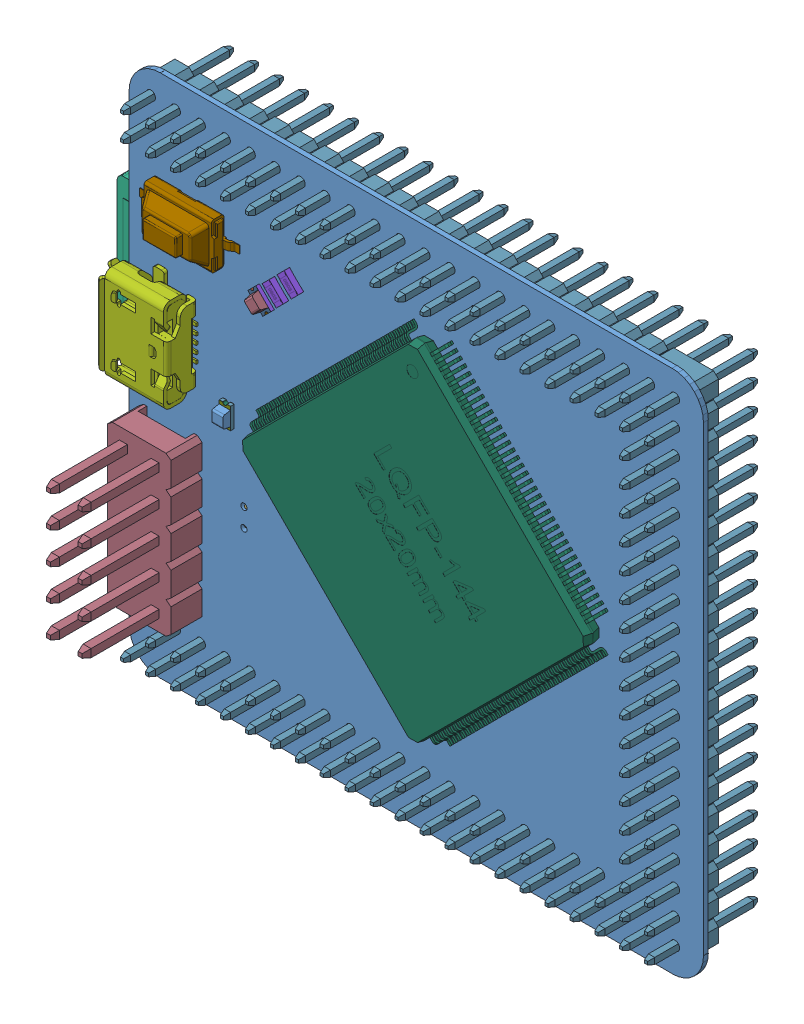
SolidWorks assembly K60最小系统, configuration Default. Lengths in mm.
Overall size (48.17 42.02 15.09).
110 component instances, 33 part files, 0 mates.
Components (placement in the parent):
- BoardK60-1: BoardK60 [默认] at (0 0 -0.3912) size (46.03 42.02 0.39)
- Y2K60-1: Y2K60 [默认] at origin size (3.3 2.6 1.1)
  - XTAL-OSC-3225-1: XTAL-OSC-3225 [默认] at (-24.3585 3.8353 -0.3912) x (1 0 0) z (0 0 -1) size (3.3 2.6 1.1)
    - User_Library-ASTX-H11_Pad-1: User_Library-ASTX-H11_Pad [默认] at origin size (3.3 2.6 0.8)
    - User_Library-ASTX-H11_Pad001-1: User_Library-ASTX-H11_Pad001 [默认] at origin size (2.8 2.4 0.24)
    - User_Library-ASTX-H11_Pad002-1: User_Library-ASTX-H11_Pad002 [默认] at origin size (2.7 2.3 0.04)
    - User_Library-ASTX-H11_ComponentPads-1: User_Library-ASTX-H11_ComponentPads [默认] at origin size (3.3 2.59 0.4)
- C1K60-1: C1K60 [默认] at origin size (1.6 0.8 0.6)
  - CAP-0603-1: CAP-0603 [默认] at (-30.5178 4.9482 -0.3912) x (-1 0 0) z (0 0 -1) size (1.6 0.8 0.6)
- C2K60-1: C2K60 [默认] at origin size (0.8 1.6 0.6)
  - CAP-0603-1: CAP-0603 [默认] at (-27.6812 3.9243 -0.3912) x (0 -1 0) z (0 0 -1) size (1.6 0.8 0.6)
- C3K60-1: C3K60 [默认] at origin size (1.6 0.8 0.6)
  - CAP-0603-1: CAP-0603 [默认] at (-29.7817 13.3652 -0.3912) x (1 0 0) z (0 0 -1) size (1.6 0.8 0.6)
- C4K60-1: C4K60 [默认] at origin size (1.6 0.8 0.6)
  - CAP-0603-1: CAP-0603 [默认] at (-29.5277 7.4724 -0.3912) x (1 0 0) z (0 0 -1) size (1.6 0.8 0.6)
- C8K60-1: C8K60 [默认] at origin size (1.6 0.8 0.6)
  - CAP-0603-1: CAP-0603 [默认] at (-25.7937 7.4724 -0.3912) x (1 0 0) z (0 0 -1) size (1.6 0.8 0.6)
- C9K60-1: C9K60 [默认] at origin size (0.8 1.6 0.6)
  - CAP-0603-1: CAP-0603 [默认] at (-11.1129 17.1069 -0.3912) x (0 -1 0) z (0 0 -1) size (1.6 0.8 0.6)
- C10K60-1: C10K60 [默认] at origin size (0.8 1.6 0.6)
  - CAP-0603-1: CAP-0603 [默认] at (-13.2127 17.1069 -0.3912) x (0 -1 0) z (0 0 -1) size (1.6 0.8 0.6)
- C11K60-1: C11K60 [默认] at origin size (0.8 1.6 0.6)
  - CAP-0603-1: CAP-0603 [默认] at (-6.9136 11.7221 -0.3912) x (0 1 0) z (0 0 -1) size (1.6 0.8 0.6)
- C12K60-1: C12K60 [默认] at origin size (0.8 1.6 0.6)
  - CAP-0603-1: CAP-0603 [默认] at (-9.0134 11.7221 -0.3912) x (0 1 0) z (0 0 -1) size (1.6 0.8 0.6)
- C13K60-1: C13K60 [默认] at origin size (0.8 1.6 0.6)
  - CAP-0603-1: CAP-0603 [默认] at (-11.1131 11.7221 -0.3912) x (0 1 0) z (0 0 -1) size (1.6 0.8 0.6)
- C14K60-1: C14K60 [默认] at origin size (0.8 1.6 0.6)
  - CAP-0603-1: CAP-0603 [默认] at (-13.2128 11.7221 -0.3912) x (0 1 0) z (0 0 -1) size (1.6 0.8 0.6)
- C15K60-1: C15K60 [默认] at origin size (0.8 1.6 0.6)
  - CAP-0603-1: CAP-0603 [默认] at (-17.0895 17.1069 -0.3912) x (0 -1 0) z (0 0 -1) size (1.6 0.8 0.6)
- C16K60-1: C16K60 [默认] at origin size (0.8 1.6 0.6)
  - CAP-0603-1: CAP-0603 [默认] at (-19.4135 17.1069 -0.3912) x (0 -1 0) z (0 0 -1) size (1.6 0.8 0.6)
- C17K60-1: C17K60 [默认] at origin size (3.2 1.6 1.6)
  - CaseA_3216-18-1: CaseA_3216-18 [默认] at (-6.5939 17.6783 -0.3912) x (1 0 0) z (0 1 0) size (3.2 1.6 1.6)
- C5K60-1: C5K60 [默认] at origin size (0.8 1.6 0.6)
  - CAP-0603-1: CAP-0603 [默认] at (-11.1637 26.6827 -0.3912) x (0 -1 0) z (0 0 -1) size (1.6 0.8 0.6)
- C6K60-1: C6K60 [默认] at origin size (0.8 1.6 0.6)
  - CAP-0603-1: CAP-0603 [默认] at (-13.2635 26.6827 -0.3912) x (0 -1 0) z (0 0 -1) size (1.6 0.8 0.6)
- C7K60-1: C7K60 [默认] at origin size (0.8 1.6 0.6)
  - CAP-0603-1: CAP-0603 [默认] at (-21.636 26.6827 -0.3912) x (0 -1 0) z (0 0 -1) size (1.6 0.8 0.6)
- D1K60-1: D1K60 [默认] at origin size (1.84 1.84 0.9)
  - LED-RED-0603-1: LED-RED-0603 [默认] at (-30.9986 26.3759 0) x (-0.707107 -0.707107 0) z (0 0 1) size (0.9 1.7 0.9)
    - User_Library-LTST-C190EKT_Pad-1: User_Library-LTST-C190EKT_Pad [默认] at origin size (0.9 1.7 0.28)
    - User_Library-LTST-C190EKT_Pad005-1: User_Library-LTST-C190EKT_Pad005 [默认] at origin size (0.35 0.15 0.31)
    - User_Library-LTST-C190EKT_Pad001-1: User_Library-LTST-C190EKT_Pad001 [默认] at origin size (0.9 1.7 0.01)
    - User_Library-LTST-C190EKT_Pad004-1: User_Library-LTST-C190EKT_Pad004 [默认] at origin size (0.35 0.15 0.31)
    - User_Library-LTST-C190EKT_Pad003-1: User_Library-LTST-C190EKT_Pad003 [默认] at origin size (0.8 1.7 0.02)
    - User_Library-LTST-C190EKT_Lens-1: User_Library-LTST-C190EKT_Lens [默认] at origin size (0.9 1.15 0.6)
- D2K60-1: D2K60 [默认] at origin size (0.9 1.7 0.9)
  - LED-BLUE-0603-1: LED-BLUE-0603 [默认] at (-33.7639 17.0687 0) size (0.9 1.7 0.9)
    - User_Library-LTST-C190TBKT_Pad-1: User_Library-LTST-C190TBKT_Pad [默认] at origin size (0.9 1.7 0.28)
    - User_Library-LTST-C190TBKT_Pad005-1: User_Library-LTST-C190TBKT_Pad005 [默认] at origin size (0.35 0.15 0.31)
    - User_Library-LTST-C190TBKT_Pad001-1: User_Library-LTST-C190TBKT_Pad001 [默认] at origin size (0.9 1.7 0.01)
    - User_Library-LTST-C190TBKT_Pad004-1: User_Library-LTST-C190TBKT_Pad004 [默认] at origin size (0.35 0.15 0.31)
    - User_Library-LTST-C190TBKT_Pad003-1: User_Library-LTST-C190TBKT_Pad003 [默认] at origin size (0.8 1.7 0.02)
    - User_Library-LTST-C190TBKT_Lens-1: User_Library-LTST-C190TBKT_Lens [默认] at origin size (0.9 1.15 0.6)
- D3K60-1: D3K60 [默认] at origin size (3.5 1.5 1.5)
  - Diode-SMD-1206-1: Diode-SMD-1206 [默认] at (-6.7564 26.162 -1.1312) x (1 0 0) z (0 0 -1) size (3.5 1.5 1.5)
- D4K60-1: D4K60 [默认] at origin size (3.5 1.5 1.5)
  - Diode-SMD-1206-1: Diode-SMD-1206 [默认] at (-6.7564 23.0992 -1.1312) x (1 0 0) z (0 0 -1) size (3.5 1.5 1.5)
- F1K60-1: F1K60 [默认] at origin size (3.2 1.65 0.56)
  - Fuse-1206-1: Fuse-1206 [默认] at (-12.3447 23.1397 -0.3912) x (1 0 0) z (0 1 0) size (3.2 0.56 1.65)
- L1K60-1: L1K60 [默认] at origin size (1.6 0.95 0.8)
  - Chip_Inductor-_0603_160808-1: Chip_Inductor-_0603_160808 [默认] at (-17.78 21.7423 -0.7912) x (-1 0 0) z (0 0 -1) size (1.6 0.95 0.8)
- L2K60-1: L2K60 [默认] at origin size (0.95 1.6 0.8)
  - Chip_Inductor-_0603_160808-1: Chip_Inductor-_0603_160808 [默认] at (-16.6023 11.7222 -0.7912) x (0 -1 0) z (0 0 -1) size (1.6 0.95 0.8)
- Micro_SDK60-1: Micro_SDK60 [默认] at origin size (17.82 16 2.45)
  - Micro-SD-1: Micro-SD [默认] at (-41.3232 22.4941 -0.4912) x (0 1 0) z (-1 0 0) size (16 2.45 15.25)
  - SD-Card-1: SD-Card [默认] at (-36.3913 22.5807 -1.1912) x (1 0 0) z (0 1 0) size (15 1 11.33)
- USBK60-1: USBK60 [默认] at origin size (5.43 7.98 2.94)
  - Micro-USB-SMD-1: Micro-USB-SMD [默认] at (-38.8874 20.7009 1.23) x (0 -1 0) z (-1 0 0) size (7.98 2.94 5.43)
- R1K60-1: R1K60 [默认] at origin size (1.6 0.8 0.46)
  - RES-0603-1: RES-0603 [默认] at (-30.518 3.0987 -0.6312) x (0 -1 0) z (1 0 0) size (0.8 0.46 1.6)
- R2K60-1: R2K60 [默认] at origin size (1.7 1.7 0.46)
  - RES-0603-1: RES-0603 [默认] at (-29.7766 27.5669 0.24) x (0.707107 0.707107 0) z (0.707107 -0.707107 0) size (0.8 0.46 1.6)
- R3K60-1: R3K60 [默认] at origin size (1.7 1.7 0.46)
  - RES-0603-1: RES-0603 [默认] at (-28.5828 28.7861 0.24) x (0.707107 0.707107 0) z (0.707107 -0.707107 0) size (0.8 0.46 1.6)
- R4K60-1: R4K60 [默认] at origin size (1.6 0.8 0.46)
  - RES-0603-1: RES-0603 [默认] at (-25.7684 13.3605 -0.6312) x (0 1 0) z (-1 0 0) size (0.8 0.46 1.6)
- R5K60-1: R5K60 [默认] at origin size (0.8 1.6 0.46)
  - RES-0603-1: RES-0603 [默认] at (-21.7422 11.7223 -0.6312) x (-1 0 0) z (0 -1 0) size (0.8 0.46 1.6)
- R6K60-1: R6K60 [默认] at origin size (0.8 1.6 0.46)
  - RES-0603-1: RES-0603 [默认] at (-33.9597 10.4522 -0.6312) x (1 0 0) z (0 1 0) size (0.8 0.46 1.6)
- R7K60-1: R7K60 [默认] at origin size (1.6 0.8 0.46)
  - RES-0603-1: RES-0603 [默认] at (-20.993 22.2249 -0.6312) x (0 -1 0) z (1 0 0) size (0.8 0.46 1.6)
- R8K60-1: R8K60 [默认] at origin size (0.8 1.6 0.46)
  - RES-0603-1: RES-0603 [默认] at (-21.7422 17.1067 -0.6312) x (-1 0 0) z (0 -1 0) size (0.8 0.46 1.6)
- R9K60-1: R9K60 [默认] at origin size (0.8 1.6 0.46)
  - RES-0603-1: RES-0603 [默认] at (-19.4136 11.7223 -0.6312) x (1 0 0) z (0 1 0) size (0.8 0.46 1.6)
- RSTK60-1: RSTK60 [默认] at origin size (8 3.7 2.65)
  - Switch-PB-1: Switch-PB [默认] at (-36.8444 28.8732 0) x (-1 0 0) z (0 1 0) size (8 2.65 3.7)
- U2K60-1: U2K60 [默认] at origin size (2.8 2.9 1.45)
  - SOT23-5-1: SOT23-5 [默认] at (-18.1634 26.7461 -0.3912) x (0 1 0) z (0 0 -1) size (2.9 2.8 1.45)
- Y1K60-1: Y1K60 [默认] at origin size (8.19 2.1 8.19)
  - XTAL-XYL_SMD-1: XTAL-XYL_SMD [默认] at (-31.2982 10.5185 -1.0912) x (0 -1 0) z (0.656059 0 0.75471) size (2.1 7.22 5.65)
    - XTAL-XYL-1: XTAL-XYL [默认] at (0.0959 -0.4998 -2.6168) x (0 -0.656059 0.75471) z (0 0.75471 0.656059) size (2.1 2.1 6.2)
      - User_Library-R38_100mils_Fillet-1: User_Library-R38_100mils_Fillet [默认] at origin size (2.1 2.1 6.2)
    - 零件1-1: 零件1 [默认] at (0.7193 -1.5563 -0.0297) x (0.965926 0.169801 -0.195333) z (-0.258819 0.633704 -0.728993) size (0.26 1.23 1.33)
    - 零件1-2: 零件1 [默认] at (-0.6339 -1.5286 -0.0615) x (0.939693 -0.224385 0.258126) z (0.34202 0.616494 -0.709195) size (0.26 1.23 1.33)
- CN4K60-1: CN4K60 [默认] at origin size (5.08 12.7 11.5)
  - Pin-Header-2.54-Double-10-1: Pin-Header-2.54-Double-10 [默认] at (-38.3285 8.0263 0.1) x (0 1 0) z (-1 0 0) size (12.7 11.5 5.08)
- CN1K60-1: CN1K60 [默认] at origin size (4 39.9 8.8)
  - Pin-Header-2.00-Double-40-1: Pin-Header-2.00-Double-40 [默认] at (0.9966 16.9896 -0.4912) x (0 -1 0) z (-1 0 0) size (39.9 8.8 4)
- CN2K60-1: CN2K60 [默认] at origin size (39.9 4 8.8)
  - Pin-Header-2.00-Double-40-1: Pin-Header-2.00-Double-40 [默认] at (-20.9896 34.9966 -0.4912) x (1 0 0) z (0 -1 0) size (39.9 8.8 4)
- CN3K60-1: CN3K60 [默认] at origin size (39.9 4 8.8)
  - Pin-Header-2.00-Double-40-1: Pin-Header-2.00-Double-40 [默认] at (-20.9896 -1.0034 -0.4912) x (1 0 0) z (0 -1 0) size (39.9 8.8 4)
- U1K60-1: U1K60 [默认] at origin size (31.11 31.11 1.6)
  - LQFP-144-20x20mm-1: LQFP-144-20x20mm [默认] at (-8.9824 11.6704 1) x (0.707107 0.707107 0) z (0.707107 -0.707107 0) size (22 1.6 22)
